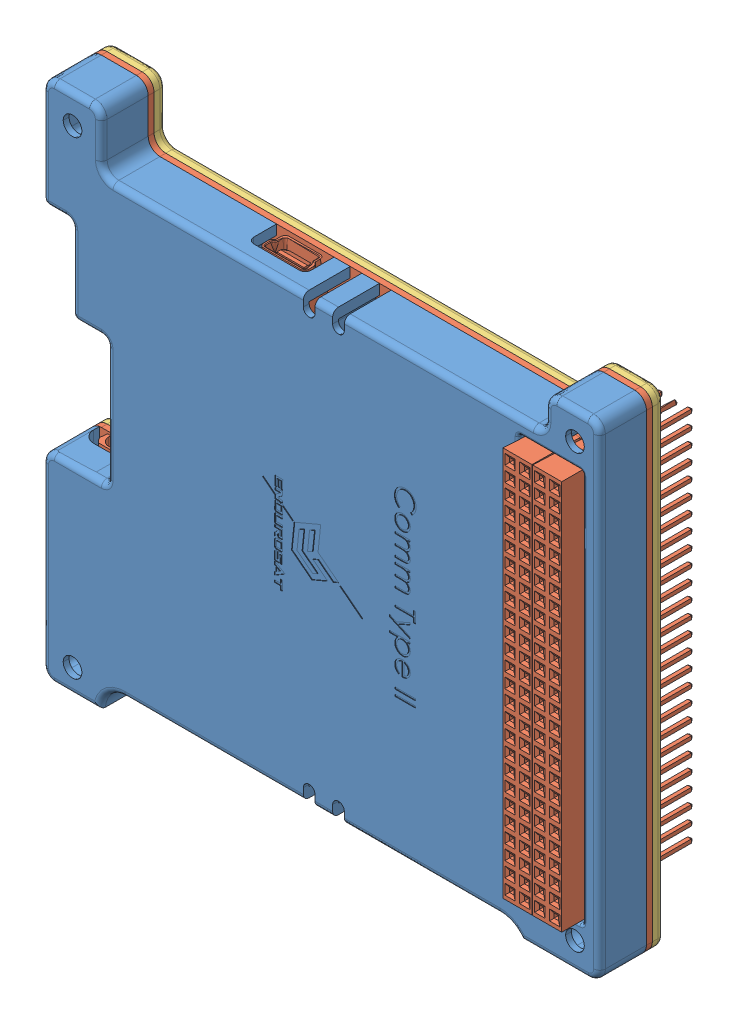
SolidWorks assembly UHF_comm_type_II, configuration Default. Lengths in mm.
Overall size (97.88 89.01 26.68).
4 component instances, 3 part files, 0 mates.
Components (placement in the parent):
- UHF_comm_type_II.STEP-1: UHF_comm_type_II.STEP [Default] at origin size (97.88 89.01 26.68)
  - UHF_BOX.STEP-1: UHF_BOX.STEP [Default] at (-90.205 -23.549 76.8824) size (95 89 8.01)
  - UHF_PCB_STEP.STEP-1: UHF_PCB_STEP.STEP [Default] at (-39.659 9.6582 83.8824) size (97.88 89.01 26.68)
  - UHF_BOX-bottom-part(nif).STEP-1: UHF_BOX-bottom-part(nif).STEP [Default] at (-24.9069 125.9519 81.8824) x (1 0 0) z (0 -1 0) size (95 2.01 89)
